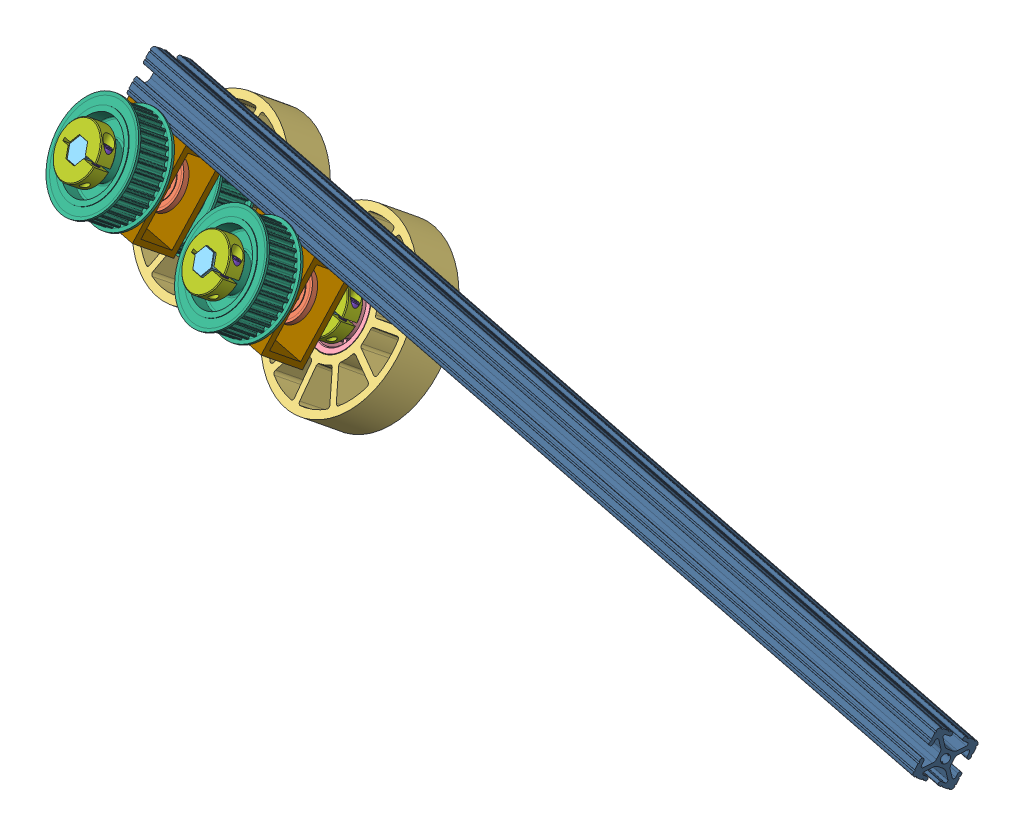
SolidWorks assembly Intake wheel assembly, configuration Default. Lengths in mm.
Overall size (700.28 186.47 258.79).
40 component instances, 10 part files, 75 mates.
Components (placement in the parent):
- intake arm with bearing-1: intake arm with bearing [Default] at (-59.0352 60.5384 -159.3422) x (0.963851 0.07724 0.254999) z (-0.088066 -0.810913 0.578502) size (152.4 7.94 38.1)
  - intake arm-1: intake arm [Default] at (153.6814 89.6919 120.1574) x (-1 0 0) z (0 0 1) size (152.4 5.59 38.1)
  - Hex Bearing .5 in internal-2: Hex Bearing .5 in internal [Default] at (20.3314 83.3419 101.1074) size (31.12 7.94 31.12)
  - Hex Bearing .5 in internal-3: Hex Bearing .5 in internal [Default] at (134.6314 83.3419 101.1074) size (31.12 7.94 31.12)
- intake wheel-1: intake wheel [Default] at (-60.0999 40.6628 -5.9946) x (0.963851 0.07724 0.254999) z (-0.251466 0.580046 0.774797) size (101.6 101.6 25.74)
  - 4IN Compliant Wheel FINAL Overmold-1: 4IN Compliant Wheel FINAL Overmold [Default] at (-16.2374 3.8509 18.652) size (101.6 101.6 25.74)
  - 2in Wheel Intergrated 0500 HEX Hub-1: 2in Wheel Intergrated 0500 HEX Hub [Default] at (-16.2374 3.8509 5.952) x (-1 0 0) z (0 0 -1) size (41.91 41.91 25.4)
- Hex shaft 0.5-3: Hex shaft 0.5 [Default] at (41.0558 36.8856 -2.4683) x (0.558193 0.740891 -0.373497) z (-0.251466 0.580046 0.774797) size (14.66 12.7 127)
- Hex shaft 0.5-4: Hex shaft 0.5 [Default] at (-68.6492 27.0092 -33.0478) x (-0.405658 0.663652 -0.628497) z (-0.251466 0.580046 0.774797) size (14.66 12.7 127)
- 0.5 Hex 2.21 Di pulley-2: 0.5 Hex 2.21 Di pulley [Default] at (-82.8442 59.7124 10.6329) x (0.558193 0.740891 -0.373497) z (-0.251466 0.580046 0.774797) size (60 60 22)
- am-1238+Collar+Clamp,+0.5''+Hex+Bore,+Aluminum working-1: am-1238+Collar+Clamp,+0.5''+Hex+Bore,+Aluminum working [Default] at (-71.279 33.0751 -24.9452) x (0.558193 0.740891 -0.373497) z (0.790686 -0.338565 0.510087) size (31.47 9.53 31.5)
  - am-1238 Clamp Only-1: am-1238 Clamp Only [Default] at origin size (31.47 9.53 31.5)
  - am-1238 Screw Only_91251A194-1: am-1238 Screw Only_91251A194 [Default] at (10.7699 4.7625 7.747) size (6.86 6.86 17.11)
- am-1238+Collar+Clamp,+0.5''+Hex+Bore,+Aluminum working-3: am-1238+Collar+Clamp,+0.5''+Hex+Bore,+Aluminum working [Default] at (38.8875 41.8874 4.2128) x (0.405658 -0.663652 0.628497) z (-0.878753 -0.472348 0.068415) size (31.47 9.53 31.5)
  - am-1238 Clamp Only-1: am-1238 Clamp Only [Default] at origin size (31.47 9.53 31.5)
  - am-1238 Screw Only_91251A194-1: am-1238 Screw Only_91251A194 [Default] at (10.7699 4.7625 7.747) size (6.86 6.86 17.11)
- 0.5 Hex 2.21 Di pulley-3: 0.5 Hex 2.21 Di pulley [Default] at (-95.5691 89.0598 49.8074) x (0.963851 0.07724 0.254999) z (-0.251466 0.580046 0.774797) size (60 60 22)
- 0.5 Hex 2.21 Di pulley-4: 0.5 Hex 2.21 Di pulley [Default] at (14.6281 97.8504 78.9916) x (0.963851 0.07724 0.254999) z (0.251466 -0.580046 -0.774797) size (60 60 22)
- intake wheel-2: intake wheel [Default] at (31.6327 63.9042 6.3783) x (-0.405658 0.663652 -0.628497) z (-0.251466 0.580046 0.774797) size (101.6 101.6 25.74)
  - 4IN Compliant Wheel FINAL Overmold-1: 4IN Compliant Wheel FINAL Overmold [Default] at (-16.2374 3.8509 18.652) size (101.6 101.6 25.74)
  - 2in Wheel Intergrated 0500 HEX Hub-1: 2in Wheel Intergrated 0500 HEX Hub [Default] at (-16.2374 3.8509 5.952) x (-1 0 0) z (0 0 -1) size (41.91 41.91 25.4)
- am-1238+Collar+Clamp,+0.5''+Hex+Bore,+Aluminum working-5: am-1238+Collar+Clamp,+0.5''+Hex+Bore,+Aluminum working [Default] at (43.2787 31.7583 -9.3171) x (0.963851 0.07724 0.254999) z (-0.088066 -0.810913 0.578502) size (31.47 9.53 31.5)
  - am-1238 Clamp Only-1: am-1238 Clamp Only [Default] at origin size (31.47 9.53 31.5)
  - am-1238 Screw Only_91251A194-1: am-1238 Screw Only_91251A194 [Default] at (10.7699 4.7625 7.747) size (6.86 6.86 17.11)
- am-1238+Collar+Clamp,+0.5''+Hex+Bore,+Aluminum working-6: am-1238+Collar+Clamp,+0.5''+Hex+Bore,+Aluminum working [Default] at (11.8549 104.2424 87.5035) x (0.963851 0.07724 0.254999) z (-0.088066 -0.810913 0.578502) size (31.47 9.53 31.5)
  - am-1238 Clamp Only-1: am-1238 Clamp Only [Default] at origin size (31.47 9.53 31.5)
  - am-1238 Screw Only_91251A194-1: am-1238 Screw Only_91251A194 [Default] at (10.7699 4.7625 7.747) size (6.86 6.86 17.11)
- am-1238+Collar+Clamp,+0.5''+Hex+Bore,+Aluminum working-7: am-1238+Collar+Clamp,+0.5''+Hex+Bore,+Aluminum working [Default] at (-98.3115 95.4301 58.3455) x (0.963851 0.07724 0.254999) z (-0.088066 -0.810913 0.578502) size (31.47 9.53 31.5)
  - am-1238 Clamp Only-1: am-1238 Clamp Only [Default] at origin size (31.47 9.53 31.5)
  - am-1238 Screw Only_91251A194-1: am-1238 Screw Only_91251A194 [Default] at (10.7699 4.7625 7.747) size (6.86 6.86 17.11)
- 1X2 by 2in thick-1: 1X2 by 2in thick [Default] at (50.912 98.3764 41.345) x (-0.088235 -0.810927 0.578457) z (-0.963836 -0.077098 -0.255101) size (50.8 25.4 50.8)
- 1X2 by 2in thick-2: 1X2 by 2in thick [Default] at (-59.2878 89.5615 12.1782) x (-0.088235 -0.810927 0.578457) z (-0.963836 -0.077098 -0.255101) size (50.8 25.4 50.8)
- Hex Bearing .5 in internal-9: Hex Bearing .5 in internal [Default] at (-90.8009 78.0555 35.1514) x (0.963851 0.07724 0.254999) z (-0.088066 -0.810913 0.578502) size (31.12 7.94 31.12)
- Hex Bearing .5 in internal-10: Hex Bearing .5 in internal [Default] at (19.399 86.8705 64.3182) x (0.90649 0.42168 -0.02148) z (0.339176 -0.696945 0.631844) size (31.12 7.94 31.12)
- Hex Bearing .5 in internal-11: Hex Bearing .5 in internal [Default] at (22.5926 79.5039 54.4783) x (-0.963851 -0.07724 -0.254999) z (-0.088066 -0.810913 0.578502) size (31.12 7.94 31.12)
- Hex Bearing .5 in internal-12: Hex Bearing .5 in internal [Default] at (-87.6072 70.689 25.3114) x (-0.891307 -0.450829 0.04823) z (0.377277 -0.678454 0.630367) size (31.12 7.94 31.12)
- am-1238+Collar+Clamp,+0.5''+Hex+Bore,+Aluminum working-8: am-1238+Collar+Clamp,+0.5''+Hex+Bore,+Aluminum working [Default] at (30.105 62.1455 31.2726) x (0.963851 0.07724 0.254999) z (-0.088066 -0.810913 0.578502) size (31.47 9.53 31.5)
  - am-1238 Clamp Only-1: am-1238 Clamp Only [Default] at origin size (31.47 9.53 31.5)
  - am-1238 Screw Only_91251A194-1: am-1238 Screw Only_91251A194 [Default] at (10.7699 4.7625 7.747) size (6.86 6.86 17.11)
- 80_20_1in_1in-1: 80_20_1in_1in [Default] at (562.3855 158.3858 181.5338) x (0.088235 0.810927 -0.578457) z (0.963836 0.077098 0.255101) size (25.4 25.4 698.5)
Mates (geometry in assembly coordinates):
- Coincident107: coincident anti-aligned: plane of intake arm with bearing-1/Hex Bearing .5 in internal-3 through (47.9461 37.8573 -0.0747) normal (-0.878753 -0.472348 0.068415); plane of Hex shaft 0.5-3 through (48.1231 37.452 -0.5986) normal (0.878753 0.472348 -0.068415)
- Coincident108: coincident anti-aligned: plane of intake arm with bearing-1/Hex Bearing .5 in internal-3 through (36.7683 31.849 0.7955) normal (0.088066 0.810913 -0.578502); plane of Hex shaft 0.5-3 through (36.963 31.4532 0.2703) normal (-0.088066 -0.810913 0.578502)
- Coincident111: coincident anti-aligned: plane of intake arm with bearing-1/Hex Bearing .5 in internal-2 through (-66.3215 23.5878 -26.4782) normal (-0.790686 0.338565 -0.510087); plane of Hex shaft 0.5-4 through (-65.6748 22.1431 -28.4395) normal (0.790686 -0.338565 0.510087)
- Coincident112: coincident anti-aligned: plane of intake arm with bearing-1/Hex Bearing .5 in internal-2 through (-65.2012 33.9026 -33.8368) normal (-0.088066 -0.810913 0.578502); plane of Hex shaft 0.5-4 through (-64.5564 32.4416 -35.7865) normal (0.088066 0.810913 -0.578502)
- Coincident116: coincident anti-aligned: plane of Hex shaft 0.5-4 through (-65.6748 22.1431 -28.4395) normal (0.790686 -0.338565 0.510087); plane of 0.5 Hex 2.21 Di pulley-2 through (-77.0967 48.4543 6.7294) normal (-0.790686 0.338565 -0.510087)
- Parallel46: parallel aligned: plane of Hex shaft 0.5-4 through (-100.5854 100.6751 65.3514) normal (-0.251466 0.580046 0.774797); plane of 0.5 Hex 2.21 Di pulley-2 through (-85.6104 66.0929 19.1557) normal (-0.251466 0.580046 0.774797)
- Coincident119: coincident anti-aligned: plane of Hex shaft 0.5-4 through (-61.5819 27.5755 -31.1781) normal (0.878753 0.472348 -0.068415); plane of 0.5 Hex 2.21 Di pulley-2 through (-72.9941 53.8996 3.9843) normal (-0.878753 -0.472348 0.068415)
- Parallel47: parallel aligned: plane of intake wheel-1/2in Wheel Intergrated 0500 HEX Hub-1 through (-73.4907 40.677 -19.0606) normal (0.251466 -0.580046 -0.774797); plane of Hex shaft 0.5-4 through (-68.6492 27.0092 -33.0478) normal (0.251466 -0.580046 -0.774797)
- Coincident121: coincident anti-aligned: plane of intake wheel-1/2in Wheel Intergrated 0500 HEX Hub-1 through (-77.8236 33.1631 -14.8416) normal (0.088066 0.810913 -0.578502); plane of Hex shaft 0.5-4 through (-72.7421 21.5767 -30.3092) normal (-0.088066 -0.810913 0.578502)
- Coincident122: coincident anti-aligned: plane of intake wheel-1/2in Wheel Intergrated 0500 HEX Hub-1 through (-66.6188 39.1859 -15.714) normal (-0.878753 -0.472348 0.068415); plane of Hex shaft 0.5-4 through (-61.5819 27.5755 -31.1781) normal (0.878753 0.472348 -0.068415)
- Parallel48: parallel anti-aligned: plane of intake arm with bearing-1/intake arm-1 through (55.9545 26.9969 18.8508) normal (-0.251466 0.580046 0.774797); plane of am-1238+Collar+Clamp,+0.5''+Hex+Bore,+Aluminum working-1/am-1238 Clamp Only-1 through (-71.279 33.0751 -24.9452) normal (0.251466 -0.580046 -0.774797)
- Coincident124: coincident anti-aligned: plane of Hex shaft 0.5-4 through (-65.6748 22.1431 -28.4395) normal (0.790686 -0.338565 0.510087); plane of am-1238+Collar+Clamp,+0.5''+Hex+Bore,+Aluminum working-1/am-1238 Clamp Only-1 through (-70.6998 33.7339 -12.9569) normal (-0.790686 0.338565 -0.510087)
- Coincident125: coincident anti-aligned: plane of Hex shaft 0.5-4 through (-64.5564 32.4416 -35.7865) normal (0.088066 0.810913 -0.578502); plane of am-1238+Collar+Clamp,+0.5''+Hex+Bore,+Aluminum working-1/am-1238 Clamp Only-1 through (-69.5813 44.0325 -20.3039) normal (-0.088066 -0.810913 0.578502)
- Parallel52: parallel aligned: plane of Hex shaft 0.5-3 through (41.0558 36.8856 -2.4683) normal (0.251466 -0.580046 -0.774797); plane of am-1238+Collar+Clamp,+0.5''+Hex+Bore,+Aluminum working-3/am-1238 Clamp Only-1 through (38.8875 41.8874 4.2128) normal (0.251466 -0.580046 -0.774797)
- Coincident137: coincident anti-aligned: plane of Hex shaft 0.5-3 through (33.9885 36.3193 -4.3381) normal (-0.878753 -0.472348 0.068415); plane of am-1238+Collar+Clamp,+0.5''+Hex+Bore,+Aluminum working-3/am-1238 Clamp Only-1 through (29.425 46.846 9.723) normal (0.878753 0.472348 -0.068415)
- Coincident138: coincident anti-aligned: plane of Hex shaft 0.5-3 through (48.1231 37.452 -0.5986) normal (0.878753 0.472348 -0.068415); plane of am-1238+Collar+Clamp,+0.5''+Hex+Bore,+Aluminum working-3/am-1238 Clamp Only-1 through (43.5595 47.9787 13.4624) normal (-0.878753 -0.472348 0.068415)
- Coincident139: coincident anti-aligned: plane of Hex shaft 0.5-3 through (44.0303 32.0195 2.14) normal (0.790686 -0.338565 0.510087); plane of am-1238+Collar+Clamp,+0.5''+Hex+Bore,+Aluminum working-3/am-1238 Clamp Only-1 through (39.4667 42.5462 16.2011) normal (-0.790686 0.338565 -0.510087)
- Coincident145: coincident anti-aligned: plane of intake arm with bearing-1/Hex Bearing .5 in internal-3 through (51.1126 42.8751 7.441) normal (-0.251466 0.580046 0.774797); plane of am-1238+Collar+Clamp,+0.5''+Hex+Bore,+Aluminum working-3/am-1238 Clamp Only-1 through (38.8875 41.8874 4.2128) normal (0.251466 -0.580046 -0.774797)
- Coincident148: coincident anti-aligned: plane of intake wheel-1/2in Wheel Intergrated 0500 HEX Hub-1 through (-78.5917 67.2536 -7.8298) normal (-0.251466 0.580046 0.774797); plane of 0.5 Hex 2.21 Di pulley-2 through (-80.0781 53.3319 2.1101) normal (0.251466 -0.580046 -0.774797)
- Coincident149: coincident anti-aligned: plane of intake wheel-1/2in Wheel Intergrated 0500 HEX Hub-1 through (-73.4907 40.677 -19.0606) normal (0.251466 -0.580046 -0.774797); plane of am-1238+Collar+Clamp,+0.5''+Hex+Bore,+Aluminum working-1/am-1238 Clamp Only-1 through (-73.6742 38.6001 -17.5653) normal (-0.251466 0.580046 0.774797)
- Coincident150: coincident anti-aligned: plane of intake arm with bearing-1/Hex Bearing .5 in internal-2 through (-65.1761 33.5562 -23.3246) normal (-0.251466 0.580046 0.774797); plane of am-1238+Collar+Clamp,+0.5''+Hex+Bore,+Aluminum working-1/am-1238 Clamp Only-1 through (-71.279 33.0751 -24.9452) normal (0.251466 -0.580046 -0.774797)
- Parallel54: parallel aligned: plane of Hex shaft 0.5-4 through (-100.5854 100.6751 65.3514) normal (-0.251466 0.580046 0.774797); plane of 0.5 Hex 2.21 Di pulley-3 through (-98.3353 95.4403 58.3302) normal (-0.251466 0.580046 0.774797)
- Coincident152: coincident anti-aligned: plane of Hex shaft 0.5-4 through (-72.7421 21.5767 -30.3092) normal (-0.088066 -0.810913 0.578502); plane of 0.5 Hex 2.21 Di pulley-3 through (-96.9056 77.234 44.0297) normal (0.088066 0.810913 -0.578502)
- Coincident153: coincident anti-aligned: plane of Hex shaft 0.5-4 through (-61.5819 27.5755 -31.1781) normal (0.878753 0.472348 -0.068415); plane of 0.5 Hex 2.21 Di pulley-3 through (-85.719 83.2469 43.1588) normal (-0.878753 -0.472348 0.068415)
- Parallel60: parallel aligned: plane of Hex shaft 0.5-3 through (9.1197 110.5516 95.931) normal (-0.251466 0.580046 0.774797); plane of 0.5 Hex 2.21 Di pulley-4 through (11.8619 104.2309 87.5144) normal (-0.251466 0.580046 0.774797)
- Coincident163: coincident anti-aligned: plane of Hex shaft 0.5-3 through (38.0814 41.7518 -7.0767) normal (-0.790686 0.338565 -0.510087); plane of 0.5 Hex 2.21 Di pulley-4 through (4.778 103.6632 85.6402) normal (0.790686 -0.338565 0.510087)
- Parallel61: parallel anti-aligned: plane of Hex shaft 0.5-3 through (44.0303 32.0195 2.14) normal (0.790686 -0.338565 0.510087); plane of 0.5 Hex 2.21 Di pulley-4 through (18.9459 104.7986 89.3885) normal (-0.790686 0.338565 -0.510087)
- Coincident165: coincident anti-aligned: plane of Hex shaft 0.5-3 through (45.1487 42.3181 -5.2069) normal (0.088066 0.810913 -0.578502); plane of 0.5 Hex 2.21 Di pulley-4 through (8.8805 109.1085 82.8951) normal (-0.088066 -0.810913 0.578502)
- Parallel62: parallel anti-aligned: plane of am-1238+Collar+Clamp,+0.5''+Hex+Bore,+Aluminum working-3/am-1238 Clamp Only-1 through (36.4922 47.4123 11.5927) normal (-0.251466 0.580046 0.774797); plane of intake wheel-2/2in Wheel Intergrated 0500 HEX Hub-1 through (34.3004 46.1954 11.7924) normal (0.251466 -0.580046 -0.774797)
- Coincident167: coincident anti-aligned: plane of am-1238+Collar+Clamp,+0.5''+Hex+Bore,+Aluminum working-3/am-1238 Clamp Only-1 through (36.4922 47.4123 11.5927) normal (-0.251466 0.580046 0.774797); plane of intake wheel-2/2in Wheel Intergrated 0500 HEX Hub-1 through (34.3004 46.1954 11.7924) normal (0.251466 -0.580046 -0.774797)
- Coincident169: coincident anti-aligned: plane of Hex shaft 0.5-3 through (45.1487 42.3181 -5.2069) normal (0.088066 0.810913 -0.578502); plane of intake wheel-2/2in Wheel Intergrated 0500 HEX Hub-1 through (40.6417 52.8493 8.869) normal (-0.088066 -0.810913 0.578502)
- Coincident171: coincident anti-aligned: plane of Hex shaft 0.5-3 through (33.9885 36.3193 -4.3381) normal (-0.878753 -0.472348 0.068415); plane of intake wheel-2/2in Wheel Intergrated 0500 HEX Hub-1 through (29.4368 46.8265 9.7414) normal (0.878753 0.472348 -0.068415)
- Parallel64: parallel anti-aligned: plane of intake arm with bearing-1/Hex Bearing .5 in internal-3 through (50.1707 38.0356 0.5139) normal (0.251466 -0.580046 -0.774797); plane of am-1238+Collar+Clamp,+0.5''+Hex+Bore,+Aluminum working-5/am-1238 Clamp Only-1 through (40.8835 37.2833 -1.9372) normal (-0.251466 0.580046 0.774797)
- Coincident176: coincident anti-aligned: plane of intake arm with bearing-1/Hex Bearing .5 in internal-3 through (50.1707 38.0356 0.5139) normal (0.251466 -0.580046 -0.774797); plane of am-1238+Collar+Clamp,+0.5''+Hex+Bore,+Aluminum working-5/am-1238 Clamp Only-1 through (40.8835 37.2833 -1.9372) normal (-0.251466 0.580046 0.774797)
- Coincident177: coincident anti-aligned: plane of Hex shaft 0.5-3 through (45.1487 42.3181 -5.2069) normal (0.088066 0.810913 -0.578502); plane of am-1238+Collar+Clamp,+0.5''+Hex+Bore,+Aluminum working-5/am-1238 Clamp Only-1 through (44.9763 42.7157 -4.6758) normal (-0.088066 -0.810913 0.578502)
- Coincident178: coincident anti-aligned: plane of Hex shaft 0.5-3 through (36.963 31.4532 0.2703) normal (-0.088066 -0.810913 0.578502); plane of am-1238+Collar+Clamp,+0.5''+Hex+Bore,+Aluminum working-5/am-1238 Clamp Only-1 through (36.7906 31.8508 0.8014) normal (0.088066 0.810913 -0.578502)
- Coincident179: coincident anti-aligned: plane of Hex shaft 0.5-3 through (33.9885 36.3193 -4.3381) normal (-0.878753 -0.472348 0.068415); plane of am-1238+Collar+Clamp,+0.5''+Hex+Bore,+Aluminum working-5/am-1238 Clamp Only-1 through (33.8162 36.7169 -3.8069) normal (0.878753 0.472348 -0.068415)
- Coincident181: coincident anti-aligned: plane of Hex shaft 0.5-3 through (33.9885 36.3193 -4.3381) normal (-0.878753 -0.472348 0.068415); plane of am-1238+Collar+Clamp,+0.5''+Hex+Bore,+Aluminum working-6/am-1238 Clamp Only-1 through (2.3924 109.201 93.0137) normal (0.878753 0.472348 -0.068415)
- Coincident182: coincident anti-aligned: plane of Hex shaft 0.5-3 through (45.1487 42.3181 -5.2069) normal (0.088066 0.810913 -0.578502); plane of am-1238+Collar+Clamp,+0.5''+Hex+Bore,+Aluminum working-6/am-1238 Clamp Only-1 through (13.5526 115.1998 92.1448) normal (-0.088066 -0.810913 0.578502)
- Coincident183: coincident anti-aligned: plane of 0.5 Hex 2.21 Di pulley-4 through (11.8619 104.2309 87.5144) normal (-0.251466 0.580046 0.774797); plane of am-1238+Collar+Clamp,+0.5''+Hex+Bore,+Aluminum working-6/am-1238 Clamp Only-1 through (11.8549 104.2424 87.5035) normal (0.251466 -0.580046 -0.774797)
- Coincident184: coincident anti-aligned: plane of 0.5 Hex 2.21 Di pulley-3 through (-98.3353 95.4403 58.3302) normal (-0.251466 0.580046 0.774797); plane of am-1238+Collar+Clamp,+0.5''+Hex+Bore,+Aluminum working-7/am-1238 Clamp Only-1 through (-98.3115 95.4301 58.3455) normal (0.251466 -0.580046 -0.774797)
- Coincident185: coincident anti-aligned: plane of Hex shaft 0.5-4 through (-64.5564 32.4416 -35.7865) normal (0.088066 0.810913 -0.578502); plane of am-1238+Collar+Clamp,+0.5''+Hex+Bore,+Aluminum working-7/am-1238 Clamp Only-1 through (-96.6139 106.3875 62.9868) normal (-0.088066 -0.810913 0.578502)
- Coincident186: coincident anti-aligned: plane of Hex shaft 0.5-4 through (-65.6748 22.1431 -28.4395) normal (0.790686 -0.338565 0.510087); plane of am-1238+Collar+Clamp,+0.5''+Hex+Bore,+Aluminum working-7/am-1238 Clamp Only-1 through (-97.7323 96.0889 70.3338) normal (-0.790686 0.338565 -0.510087)
- Concentric6: concentric aligned: circle of 1X2 by 2in thick-2; cylinder of Hex Bearing .5 in internal-9 through (-90.8009 78.0555 35.1514) axis (-0.251466 0.580046 0.774797) radius 15.5575
- Coincident196: coincident aligned: plane of 1X2 by 2in thick-2 through (-114.6379 100.3781 18.899) normal (-0.251466 0.580046 0.774797); circle of Hex Bearing .5 in internal-9
- Parallel67: parallel anti-aligned: plane of 1X2 by 2in thick-1 through (0.8706 93.7268 32.6825) normal (-0.251466 0.580046 0.774797); plane of Hex Bearing .5 in internal-11 through (15.1897 74.3752 46.1623) normal (0.251466 -0.580046 -0.774797)
- Coincident200: coincident aligned: plane of 1X2 by 2in thick-1 through (1.9491 94.4598 28.3859) normal (0.251466 -0.580046 -0.774797); circle of Hex Bearing .5 in internal-11
- Coincident201: coincident anti-aligned: plane of Hex shaft 0.5-3 through (33.9885 36.3193 -4.3381) normal (-0.878753 -0.472348 0.068415); plane of Hex Bearing .5 in internal-11 through (18.4933 74.0629 57.2212) normal (0.878753 0.472348 -0.068415)
- Coincident202: coincident anti-aligned: plane of Hex shaft 0.5-3 through (45.1487 42.3181 -5.2069) normal (0.088066 0.810913 -0.578502); plane of Hex Bearing .5 in internal-11 through (19.6135 84.3777 49.8626) normal (-0.088066 -0.810913 0.578502)
- Concentric7: concentric anti-aligned: cylinder of 1X2 by 2in thick-1 through (24.1894 75.8206 49.5583) axis (-0.251466 0.580046 0.774797) radius 14.224; cylinder of Hex Bearing .5 in internal-11 through (22.5926 79.5039 54.4783) axis (0.251466 -0.580046 -0.774797) radius 14.2748
- Parallel68: parallel anti-aligned: plane of 1X2 by 2in thick-1 through (-4.4381 109.193 48.0658) normal (-0.251466 0.580046 0.774797); plane of Hex Bearing .5 in internal-10 through (31.9049 97.1141 68.904) normal (0.251466 -0.580046 -0.774797)
- Concentric8: concentric aligned: cylinder of 1X2 by 2in thick-1 through (24.1894 75.8206 49.5583) axis (-0.251466 0.580046 0.774797) radius 14.224; cylinder of Hex Bearing .5 in internal-10 through (19.399 86.8705 64.3182) axis (-0.251466 0.580046 0.774797) radius 14.2748
- Concentric9: concentric aligned: cylinder of 1X2 by 2in thick-1 through (24.1894 75.8206 49.5583) axis (-0.251466 0.580046 0.774797) radius 14.224; cylinder of Hex Bearing .5 in internal-10 through (19.399 86.8705 64.3182) axis (-0.251466 0.580046 0.774797) radius 14.2748
- Coincident208: coincident aligned: plane of 1X2 by 2in thick-1 through (-4.4381 109.193 48.0658) normal (-0.251466 0.580046 0.774797); circle of Hex Bearing .5 in internal-10
- Parallel70: parallel anti-aligned: plane of intake arm with bearing-1/intake arm-1 through (55.9545 26.9969 18.8508) normal (-0.251466 0.580046 0.774797); plane of 1X2 by 2in thick-2 through (-108.2507 85.6449 -0.7809) normal (0.251466 -0.580046 -0.774797)
- Coincident211: coincident anti-aligned: plane of Hex shaft 0.5-4 through (-64.5564 32.4416 -35.7865) normal (0.088066 0.810913 -0.578502); plane of Hex Bearing .5 in internal-9 through (-86.7015 83.4966 32.4084) normal (-0.088066 -0.810913 0.578502)
- Coincident212: coincident anti-aligned: plane of Hex shaft 0.5-4 through (-65.6748 22.1431 -28.4395) normal (0.790686 -0.338565 0.510087); plane of Hex Bearing .5 in internal-9 through (-87.8218 73.1818 39.767) normal (-0.790686 0.338565 -0.510087)
- Coincident213: coincident aligned: plane of 1X2 by 2in thick-2 through (-108.2507 85.6449 -0.7809) normal (0.251466 -0.580046 -0.774797); circle of Hex Bearing .5 in internal-12
- Concentric10: concentric anti-aligned: cylinder of 1X2 by 2in thick-2 through (-86.0104 67.0057 20.3915) axis (-0.251466 0.580046 0.774797) radius 14.224; cylinder of Hex Bearing .5 in internal-12 through (-87.6072 70.689 25.3114) axis (0.251466 -0.580046 -0.774797) radius 14.2748
- Coincident214: coincident anti-aligned: plane of 0.5 Hex 2.21 Di pulley-2 through (-85.6104 66.0929 19.1557) normal (-0.251466 0.580046 0.774797); plane of Hex Bearing .5 in internal-12 through (-91.271 63.2221 19.4677) normal (0.251466 -0.580046 -0.774797)
- Coincident215: coincident anti-aligned: plane of 0.5 Hex 2.21 Di pulley-3 through (-92.803 82.6793 41.2846) normal (0.251466 -0.580046 -0.774797); plane of Hex Bearing .5 in internal-9 through (-86.6764 83.1501 42.9206) normal (-0.251466 0.580046 0.774797)
- Parallel71: parallel anti-aligned: plane of intake wheel-2/2in Wheel Intergrated 0500 HEX Hub-1 through (27.9132 60.9286 31.4722) normal (-0.251466 0.580046 0.774797); plane of am-1238+Collar+Clamp,+0.5''+Hex+Bore,+Aluminum working-8/am-1238 Clamp Only-1 through (30.105 62.1455 31.2726) normal (0.251466 -0.580046 -0.774797)
- Coincident218: coincident anti-aligned: plane of Hex shaft 0.5-3 through (44.0303 32.0195 2.14) normal (0.790686 -0.338565 0.510087); plane of am-1238+Collar+Clamp,+0.5''+Hex+Bore,+Aluminum working-8/am-1238 Clamp Only-1 through (30.6842 62.8043 43.2609) normal (-0.790686 0.338565 -0.510087)
- Coincident219: coincident anti-aligned: plane of Hex shaft 0.5-3 through (33.9885 36.3193 -4.3381) normal (-0.878753 -0.472348 0.068415); plane of am-1238+Collar+Clamp,+0.5''+Hex+Bore,+Aluminum working-8/am-1238 Clamp Only-1 through (20.6425 67.1041 36.7828) normal (0.878753 0.472348 -0.068415)
- Coincident220: coincident anti-aligned: plane of intake wheel-2/2in Wheel Intergrated 0500 HEX Hub-1 through (27.9132 60.9286 31.4722) normal (-0.251466 0.580046 0.774797); plane of am-1238+Collar+Clamp,+0.5''+Hex+Bore,+Aluminum working-8/am-1238 Clamp Only-1 through (30.105 62.1455 31.2726) normal (0.251466 -0.580046 -0.774797)
- Parallel72: parallel aligned: plane of 1X2 by 2in thick-1 through (1.9491 94.4598 28.3859) normal (0.088235 0.810927 -0.578457); plane of 1X2 by 2in thick-2 through (-108.2507 85.6449 -0.7809) normal (0.088235 0.810927 -0.578457)
- Parallel73: parallel aligned: plane of 1X2 by 2in thick-1 through (1.9491 94.4598 28.3859) normal (0.251466 -0.580046 -0.774797); plane of 1X2 by 2in thick-2 through (-108.2507 85.6449 -0.7809) normal (0.251466 -0.580046 -0.774797)
- Parallel75: parallel: plane of 1X2 by 2in thick-2 through (-108.2507 85.6449 -0.7809) normal (0.088235 0.810927 -0.578457); line of 80_20_1in_1in-1 through (561.5819 155.6787 185.3881) axis (-0.963836 -0.077098 -0.255101)
- Parallel76: parallel anti-aligned: plane of 1X2 by 2in thick-2 through (-108.2507 85.6449 -0.7809) normal (0.088235 0.810927 -0.578457); plane of 80_20_1in_1in-1 through (-661.2141 46.4996 -140.0044) normal (-0.088235 -0.810927 0.578457)
- Parallel77: parallel anti-aligned: plane of 1X2 by 2in thick-2 through (-108.2507 85.6449 -0.7809) normal (0.088235 0.810927 -0.578457); plane of 80_20_1in_1in-1 through (-665.2083 55.7127 -127.6979) normal (-0.088235 -0.810927 0.578457)
- Coincident227: coincident anti-aligned: plane of 1X2 by 2in thick-2 through (-108.2507 85.6449 -0.7809) normal (0.088235 0.810927 -0.578457); plane of 80_20_1in_1in-1 through (-665.2083 55.7127 -127.6979) normal (-0.088235 -0.810927 0.578457)
- Coincident228: coincident aligned: line of 1X2 by 2in thick-2 through (-114.6379 100.3781 18.899) axis (0.251466 -0.580046 -0.774797); line of 80_20_1in_1in-1 through (-110.3819 90.5609 5.7856) axis (0.251466 -0.580046 -0.774797)
- Coincident229: coincident anti-aligned: plane of 1X2 by 2in thick-1 through (1.9491 94.4598 28.3859) normal (0.088235 0.810927 -0.578457); plane of 80_20_1in_1in-1 through (-661.2141 46.4996 -140.0044) normal (-0.088235 -0.810927 0.578457)
- Coincident230: coincident: line of 1X2 by 2in thick-2 through (-114.6379 100.3781 18.899) axis (0.963836 0.077098 0.255101); cylinder of 80_20_1in_1in-1 through (-665.2841 58.0264 -128.1105) axis (-0.963836 -0.077098 -0.255101) radius 2.1082
- Coincident231: coincident: line of 1X2 by 2in thick-1 through (-4.4381 109.193 48.0658) axis (0.963836 0.077098 0.255101); cylinder of 80_20_1in_1in-1 through (-665.2841 58.0264 -128.1105) axis (-0.963836 -0.077098 -0.255101) radius 2.1082
